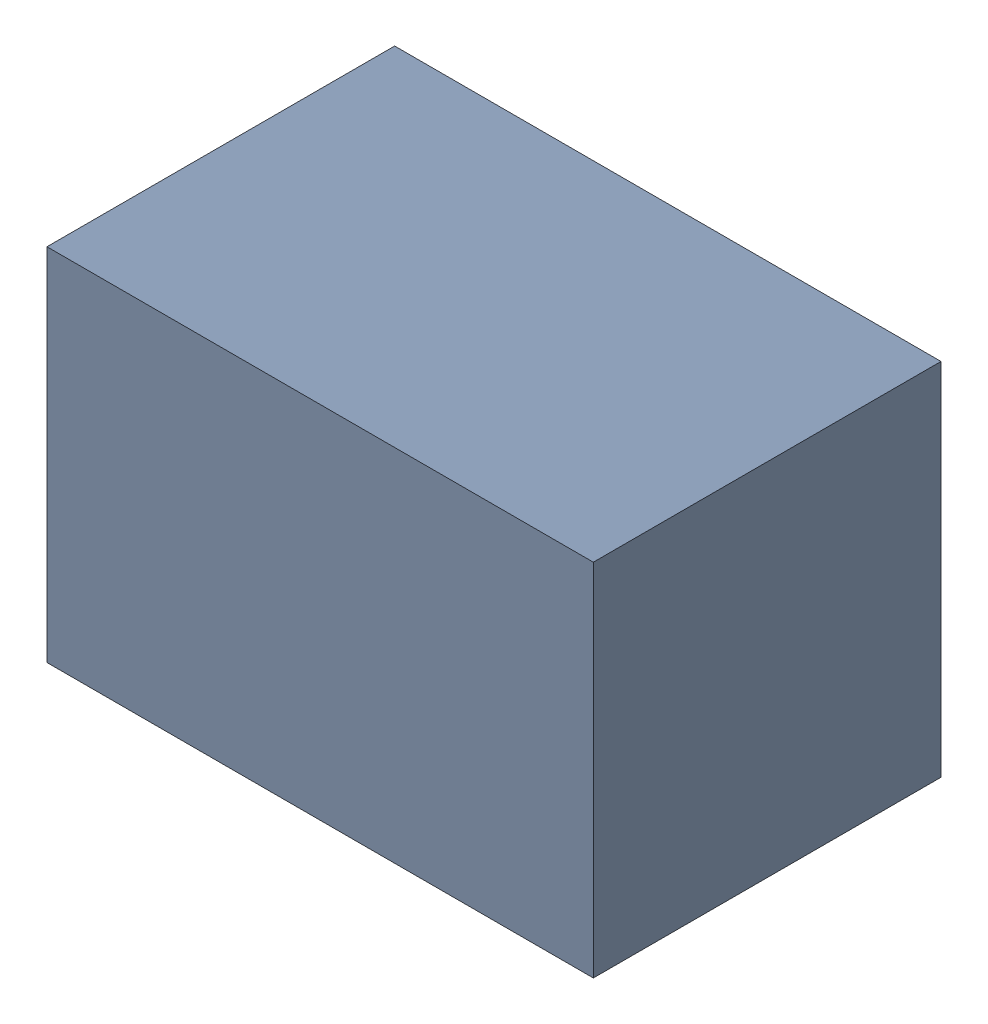
SolidWorks assembly C19, configuration Default. Lengths in mm.
Overall size (2.2 1.45 1.4).
2 component instances, 1 part files, 0 mates.
Components (placement in the parent):
- 1017092848-1: 1017092848 [Default] at (105.41 144.78 0) size (2.2 1.45 1.4)
  - Extruded_3-1: Extruded_3 [Default] at origin size (2.2 1.45 1.4)
